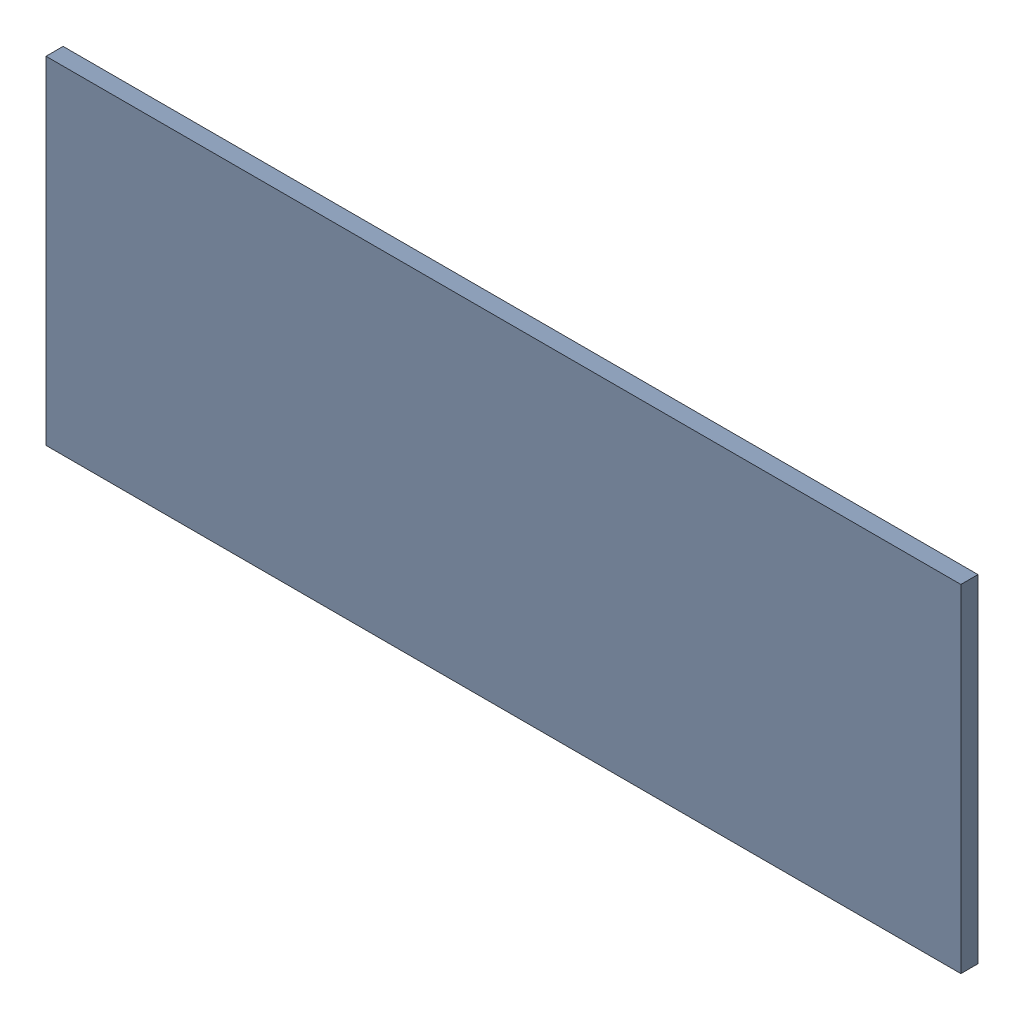
SolidWorks assembly Pad RAK4600-29(29.2mm,21.25mm) on Top Layer, configuration Predeterminado. Lengths in mm.
Overall size (1.9 0.7 0.04).
2 component instances, 1 part files, 0 mates.
Components (placement in the parent):
- Pad RAK4600-29(29.2mm,21.25mm) on Top Layer-1-1: Pad RAK4600-29(29.2mm,21.25mm) on Top Layer-1 [Predeterminado] at (-68.317 -44.187 -0.0457) size (1.9 0.7 0.04)
  - Pad RAK4600-29(29.2mm,21.25mm) on Top Layer-Part-1-1: Pad RAK4600-29(29.2mm,21.25mm) on Top Layer-Part-1 [Predeterminado] at origin size (1.9 0.7 0.04)
